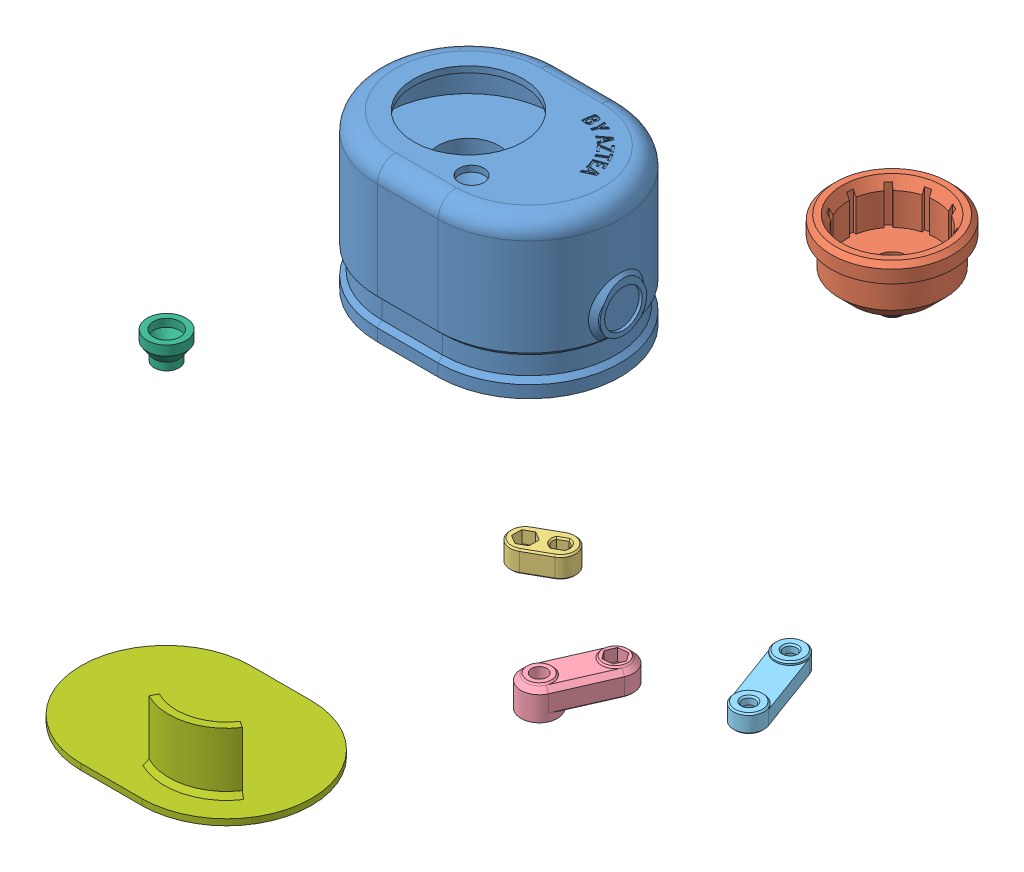
SolidWorks assembly 3DPrint, configuration Default. Lengths in mm.
Overall size (187.22 131.85 187.68).
7 component instances, 7 part files, 0 mates.
Components (placement in the parent):
- Shell-1: Shell [Default] at (4.8051 40.5165 54.4278) size (81.48 51 60)
- Base-1: Base [Default] at (102.9884 63.3414 13.1716) x (0.401974 0 -0.915651) z (0.915651 0 0.401974) size (40 27 40)
- Crank_M-1: Crank_M [Default] at (64.4954 5.6276 83.818) x (-0.870684 0 0.491843) z (-0.491843 0 -0.870684) size (18.5 7 10)
- Rocker_B-1: Rocker_B [Default] at (76.0157 -19.2631 102.3654) x (0.401974 0 -0.915651) z (0.915651 0 0.401974) size (31 10 12)
- Link-1: Link [Default] at (112.4696 -13.4529 56.2167) x (0.34616 0 0.938176) z (-0.938176 0 0.34616) size (33 6 10)
- Bushing-1: Bushing [Default] at (-49.8382 -19.6269 99.1381) x (0.95303 0 0.302877) z (-0.302877 0 0.95303) size (12.8 9 12.8)
- BasePlate-1: BasePlate [Default] at (-2.6279 -40.3344 146.6) size (75.8 21.5 55.8)
